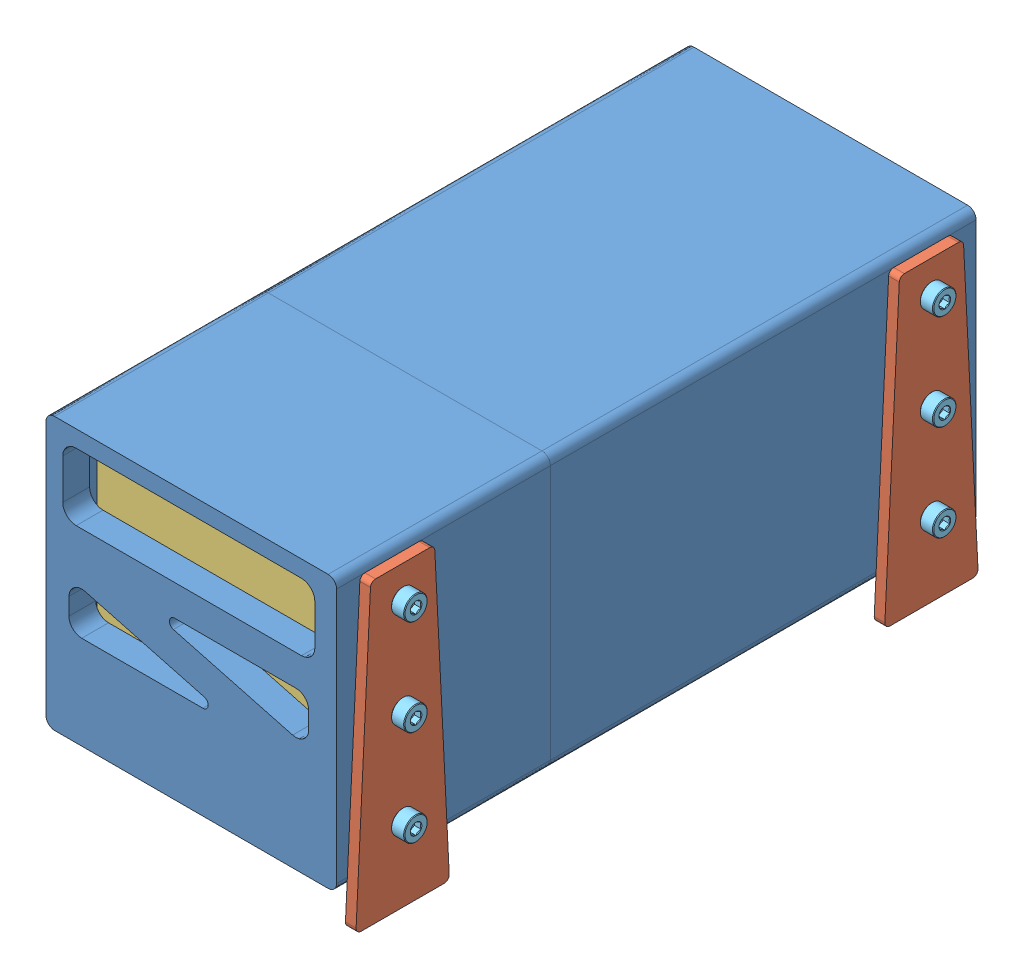
SolidWorks assembly EL-A0104-AA-LV Battery Assembly, configuration Default. Lengths in mm.
Overall size (94.06 91.44 190.78).
16 component instances, 5 part files, 35 mates.
Components (placement in the parent):
- EL-50060-AA-LV Battery Enclosure-2: EL-50060-AA-LV Battery Enclosure [Default] at (103.4038 95.6364 30.9853) size (86.72 81.15 190.78)
- EL-30061-AA-LV Battery Mounting Tab-1: EL-30061-AA-LV Battery Mounting Tab [Default] at (147.5118 95.6364 125.9313) x (0 0 -1) z (0 -1 0) size (27.78 3.17 88.9)
- EL-30061-AA-LV Battery Mounting Tab-2: EL-30061-AA-LV Battery Mounting Tab [Default] at (147.5118 95.6364 -31.8247) x (0 0 -1) z (0 -1 0) size (27.78 3.17 88.9)
- EL-00004-AA-Aegies-12 V 20 Ah Battery-2: EL-00004-AA-Aegies-12 V 20 Ah Battery [Default] at (103.4038 55.5044 123.3053) x (0 0 1) z (0 1 0) size (167.64 76.2 76.2)
- FS-Heat Set Insert, M4x7-4.7 (94180A351)-1: FS-Heat Set Insert, M4x7-4.7 (94180A351) [94180A351] at (145.1618 124.2114 201.2513) x (0 -0.392341 -0.91982) z (1 0 0) size (6.35 6.35 4.7)
- FS-Heat Set Insert, M4x7-4.7 (94180A351)-2: FS-Heat Set Insert, M4x7-4.7 (94180A351) [94180A351] at (145.1618 95.6364 201.2513) x (0 -0.348719 -0.937227) z (1 0 0) size (6.35 6.35 4.7)
- FS-Heat Set Insert, M4x7-4.7 (94180A351)-3: FS-Heat Set Insert, M4x7-4.7 (94180A351) [94180A351] at (145.1618 67.0614 201.2513) x (0 -0.267668 -0.963511) z (1 0 0) size (6.35 6.35 4.7)
- FS-Heat Set Insert, M4x7-4.7 (94180A351)-4: FS-Heat Set Insert, M4x7-4.7 (94180A351) [94180A351] at (145.1618 67.0614 43.4953) x (0 -0.267487 -0.963562) z (1 0 0) size (6.35 6.35 4.7)
- FS-Heat Set Insert, M4x7-4.7 (94180A351)-5: FS-Heat Set Insert, M4x7-4.7 (94180A351) [94180A351] at (145.1618 95.6364 43.4953) x (0 -0.337845 -0.941202) z (1 0 0) size (6.35 6.35 4.7)
- FS-Heat Set Insert, M4x7-4.7 (94180A351)-6: FS-Heat Set Insert, M4x7-4.7 (94180A351) [94180A351] at (145.1618 124.2114 43.4953) x (0 -0.264568 -0.964367) z (1 0 0) size (6.35 6.35 4.7)
- BR-Black Oxide C12.9 SHCS, M4x0.7-8 (91290A140)-2: BR-Black Oxide C12.9 SHCS, M4x0.7-8 (91290A140) [91290A140] at (148.6868 95.6364 43.4953) x (0 0 -1) z (1 0 0) size (7 7 12.17)
- BR-Black Oxide C12.9 SHCS, M4x0.7-8 (91290A140)-3: BR-Black Oxide C12.9 SHCS, M4x0.7-8 (91290A140) [91290A140] at (148.6868 95.6364 201.2513) x (0 0 -1) z (1 0 0) size (7 7 12.17)
- BR-Black Oxide C12.9 SHCS, M4x0.7-8 (91290A140)-4: BR-Black Oxide C12.9 SHCS, M4x0.7-8 (91290A140) [91290A140] at (148.6868 124.2114 201.2513) x (0 0 -1) z (1 0 0) size (7 7 12.17)
- BR-Black Oxide C12.9 SHCS, M4x0.7-8 (91290A140)-5: BR-Black Oxide C12.9 SHCS, M4x0.7-8 (91290A140) [91290A140] at (148.6868 67.0614 43.4953) x (0 0 -1) z (1 0 0) size (7 7 12.17)
- BR-Black Oxide C12.9 SHCS, M4x0.7-8 (91290A140)-6: BR-Black Oxide C12.9 SHCS, M4x0.7-8 (91290A140) [91290A140] at (148.6868 67.0614 201.2513) x (0 0 -1) z (1 0 0) size (7 7 12.17)
- BR-Black Oxide C12.9 SHCS, M4x0.7-8 (91290A140)-7: BR-Black Oxide C12.9 SHCS, M4x0.7-8 (91290A140) [91290A140] at (148.6868 124.2114 43.4953) x (0 0 -1) z (1 0 0) size (7 7 12.17)
Mates (geometry in assembly coordinates):
- Concentric1: concentric aligned: cylinder of EL-50060-AA-LV Battery Enclosure-2 through (128.0118 124.2114 201.2513) axis (1 0 0) radius 3.025; circle of LV-Mounting-Tab-1
- Concentric2: concentric aligned: cylinder of EL-50060-AA-LV Battery Enclosure-2 through (128.0118 95.6364 201.2513) axis (1 0 0) radius 3.025; cylinder of EL-30061-AA-LV Battery Mounting Tab-1 through (150.6868 95.6364 201.2513) axis (1 0 0) radius 2.25
- Concentric3: concentric aligned: cylinder of EL-50060-AA-LV Battery Enclosure-2 through (128.0118 67.0614 201.2513) axis (1 0 0) radius 3.025; cylinder of EL-30061-AA-LV Battery Mounting Tab-1 through (150.6868 67.0614 201.2513) axis (1 0 0) radius 2.25
- Coincident1: coincident anti-aligned: plane of EL-50060-AA-LV Battery Enclosure-2 through (147.5118 95.6364 30.9853) normal (1 0 0); plane of EL-30061-AA-LV Battery Mounting Tab-1 through (147.5118 132.1474 209.3266) normal (-1 0 0)
- Concentric4: concentric aligned: cylinder of EL-50060-AA-LV Battery Enclosure-2 through (128.0118 124.2114 43.4953) axis (1 0 0) radius 3.025; cylinder of LV-Mounting-Tab-2 through (150.6868 124.2114 43.4953) axis (1 0 0) radius 2.25
- Concentric5: concentric aligned: cylinder of EL-50060-AA-LV Battery Enclosure-2 through (128.0118 95.6364 43.4953) axis (1 0 0) radius 3.025; cylinder of LV-Mounting-Tab-2 through (150.6868 95.6364 43.4953) axis (1 0 0) radius 2.25
- Concentric6: concentric aligned: cylinder of EL-50060-AA-LV Battery Enclosure-2 through (128.0118 67.0614 43.4953) axis (1 0 0) radius 3.025; cylinder of LV-Mounting-Tab-2 through (150.6868 67.0614 43.4953) axis (1 0 0) radius 2.25
- Coincident2: coincident anti-aligned: plane of EL-50060-AA-LV Battery Enclosure-2 through (147.5118 95.6364 30.9853) normal (1 0 0); plane of LV-Mounting-Tab-2 through (147.5118 132.1474 51.5706) normal (-1 0 0)
- Concentric7: concentric aligned: cylinder of EL-50060-AA-LV Battery Enclosure-2 through (128.0118 124.2114 201.2513) axis (1 0 0) radius 3.025; circle of FS-Heat Set Insert, M4x7-4.7 (94180A351)-1
- Coincident3: coincident aligned: plane of EL-50060-AA-LV Battery Enclosure-2 through (147.5118 95.6364 30.9853) normal (1 0 0); circle of FS-Heat Set Insert, M4x7-4.7 (94180A351)-1
- Concentric8: concentric aligned: cylinder of EL-50060-AA-LV Battery Enclosure-2 through (128.0118 95.6364 201.2513) axis (1 0 0) radius 3.025; cylinder of FS-Heat Set Insert, M4x7-4.7 (94180A351)-2 through (147.5118 95.6364 201.2513) axis (1 0 0) radius 3.175
- Coincident4: coincident aligned: plane of EL-50060-AA-LV Battery Enclosure-2 through (147.5118 95.6364 30.9853) normal (1 0 0); circle of FS-Heat Set Insert, M4x7-4.7 (94180A351)-2
- Concentric9: concentric aligned: cylinder of EL-50060-AA-LV Battery Enclosure-2 through (128.0118 67.0614 201.2513) axis (1 0 0) radius 3.025; cylinder of FS-Heat Set Insert, M4x7-4.7 (94180A351)-3 through (147.5118 67.0614 201.2513) axis (1 0 0) radius 3.175
- Coincident5: coincident aligned: plane of EL-50060-AA-LV Battery Enclosure-2 through (147.5118 95.6364 30.9853) normal (1 0 0); circle of FS-Heat Set Insert, M4x7-4.7 (94180A351)-3
- Concentric10: concentric aligned: cylinder of EL-50060-AA-LV Battery Enclosure-2 through (128.0118 67.0614 43.4953) axis (1 0 0) radius 3.025; cylinder of FS-Heat Set Insert, M4x7-4.7 (94180A351)-4 through (147.5118 67.0614 43.4953) axis (1 0 0) radius 3.175
- Coincident6: coincident aligned: plane of EL-50060-AA-LV Battery Enclosure-2 through (147.5118 95.6364 30.9853) normal (1 0 0); circle of FS-Heat Set Insert, M4x7-4.7 (94180A351)-4
- Concentric11: concentric aligned: cylinder of EL-50060-AA-LV Battery Enclosure-2 through (128.0118 95.6364 43.4953) axis (1 0 0) radius 3.025; cylinder of FS-Heat Set Insert, M4x7-4.7 (94180A351)-5 through (147.5118 95.6364 43.4953) axis (1 0 0) radius 3.175
- Coincident7: coincident aligned: plane of EL-50060-AA-LV Battery Enclosure-2 through (147.5118 95.6364 30.9853) normal (1 0 0); circle of FS-Heat Set Insert, M4x7-4.7 (94180A351)-5
- Concentric12: concentric aligned: cylinder of EL-50060-AA-LV Battery Enclosure-2 through (128.0118 124.2114 43.4953) axis (1 0 0) radius 3.025; cylinder of FS-Heat Set Insert, M4x7-4.7 (94180A351)-6 through (147.5118 124.2114 43.4953) axis (1 0 0) radius 3.175
- Coincident8: coincident aligned: plane of EL-50060-AA-LV Battery Enclosure-2 through (147.5118 95.6364 30.9853) normal (1 0 0); circle of FS-Heat Set Insert, M4x7-4.7 (94180A351)-6
- Distance1: distance = 0.508 mm anti-aligned: plane of EL-00004-AA-Aegies-12 V 20 Ah Battery-2 through (103.4038 131.7044 123.3053) normal (0 1 0); plane of EL-50060-AA-LV Battery Enclosure-2 through (60.7958 132.2124 213.7613) normal (0 -1 0)
- Distance2: distance = 0.508 mm anti-aligned: plane of EL-00004-AA-Aegies-12 V 20 Ah Battery-2 through (141.5038 131.7044 39.4853) normal (1 0 0); plane of EL-50060-AA-LV Battery Enclosure-2 through (142.0118 136.2124 213.7613) normal (-1 0 0)
- Coincident12: coincident anti-aligned: plane of EL-50060-AA-LV Battery Enclosure-2 through (103.4038 95.6364 39.4853) normal (0 0 1); plane of EL-00004-AA-Aegies-12 V 20 Ah Battery-2 through (141.5038 131.7044 39.4853) normal (0 0 -1)
- Concentric13: concentric anti-aligned: cylinder of EL-30061-AA-LV Battery Mounting Tab-1 through (150.6868 124.2114 201.2513) axis (1 0 0) radius 2.25; cylinder of BR-Black Oxide C12.9 SHCS, M4x0.7-8 (91290A140)-4 through (142.6868 124.2114 201.2513) axis (-1 0 0) radius 2
- Coincident13: coincident anti-aligned: plane of EL-30061-AA-LV Battery Mounting Tab-1 through (150.6868 132.1474 209.3266) normal (1 0 0); plane of BR-Black Oxide C12.9 SHCS, M4x0.7-8 (91290A140)-4 through (150.6868 127.5114 201.2513) normal (-1 0 0)
- Concentric14: concentric anti-aligned: cylinder of EL-30061-AA-LV Battery Mounting Tab-1 through (150.6868 95.6364 201.2513) axis (1 0 0) radius 2.25; cylinder of BR-Black Oxide C12.9 SHCS, M4x0.7-8 (91290A140)-3 through (142.6868 95.6364 201.2513) axis (-1 0 0) radius 2
- Coincident14: coincident anti-aligned: plane of EL-30061-AA-LV Battery Mounting Tab-1 through (150.6868 132.1474 209.3266) normal (1 0 0); plane of BR-Black Oxide C12.9 SHCS, M4x0.7-8 (91290A140)-3 through (150.6868 98.9364 201.2513) normal (-1 0 0)
- Concentric15: concentric anti-aligned: cylinder of EL-30061-AA-LV Battery Mounting Tab-1 through (150.6868 67.0614 201.2513) axis (1 0 0) radius 2.25; cylinder of BR-Black Oxide C12.9 SHCS, M4x0.7-8 (91290A140)-6 through (142.6868 67.0614 201.2513) axis (-1 0 0) radius 2
- Coincident15: coincident anti-aligned: plane of EL-30061-AA-LV Battery Mounting Tab-1 through (150.6868 132.1474 209.3266) normal (1 0 0); plane of BR-Black Oxide C12.9 SHCS, M4x0.7-8 (91290A140)-6 through (150.6868 70.3614 201.2513) normal (-1 0 0)
- Concentric16: concentric anti-aligned: cylinder of LV-Mounting-Tab-2 through (150.6868 124.2114 43.4953) axis (1 0 0) radius 2.25; cylinder of BR-Black Oxide C12.9 SHCS, M4x0.7-8 (91290A140)-7 through (142.6868 124.2114 43.4953) axis (-1 0 0) radius 2
- Coincident16: coincident anti-aligned: plane of LV-Mounting-Tab-2 through (150.6868 132.1474 51.5706) normal (1 0 0); plane of BR-Black Oxide C12.9 SHCS, M4x0.7-8 (91290A140)-7 through (150.6868 127.5114 43.4953) normal (-1 0 0)
- Concentric17: concentric anti-aligned: cylinder of LV-Mounting-Tab-2 through (150.6868 95.6364 43.4953) axis (1 0 0) radius 2.25; cylinder of BR-Black Oxide C12.9 SHCS, M4x0.7-8 (91290A140)-2 through (142.6868 95.6364 43.4953) axis (-1 0 0) radius 2
- Coincident17: coincident anti-aligned: plane of LV-Mounting-Tab-2 through (150.6868 132.1474 51.5706) normal (1 0 0); plane of BR-Black Oxide C12.9 SHCS, M4x0.7-8 (91290A140)-2 through (150.6868 98.9364 43.4953) normal (-1 0 0)
- Concentric18: concentric anti-aligned: cylinder of LV-Mounting-Tab-2 through (150.6868 67.0614 43.4953) axis (1 0 0) radius 2.25; cylinder of BR-Black Oxide C12.9 SHCS, M4x0.7-8 (91290A140)-5 through (142.6868 67.0614 43.4953) axis (-1 0 0) radius 2
- Coincident18: coincident anti-aligned: plane of LV-Mounting-Tab-2 through (150.6868 132.1474 51.5706) normal (1 0 0); plane of BR-Black Oxide C12.9 SHCS, M4x0.7-8 (91290A140)-5 through (150.6868 70.3614 43.4953) normal (-1 0 0)
